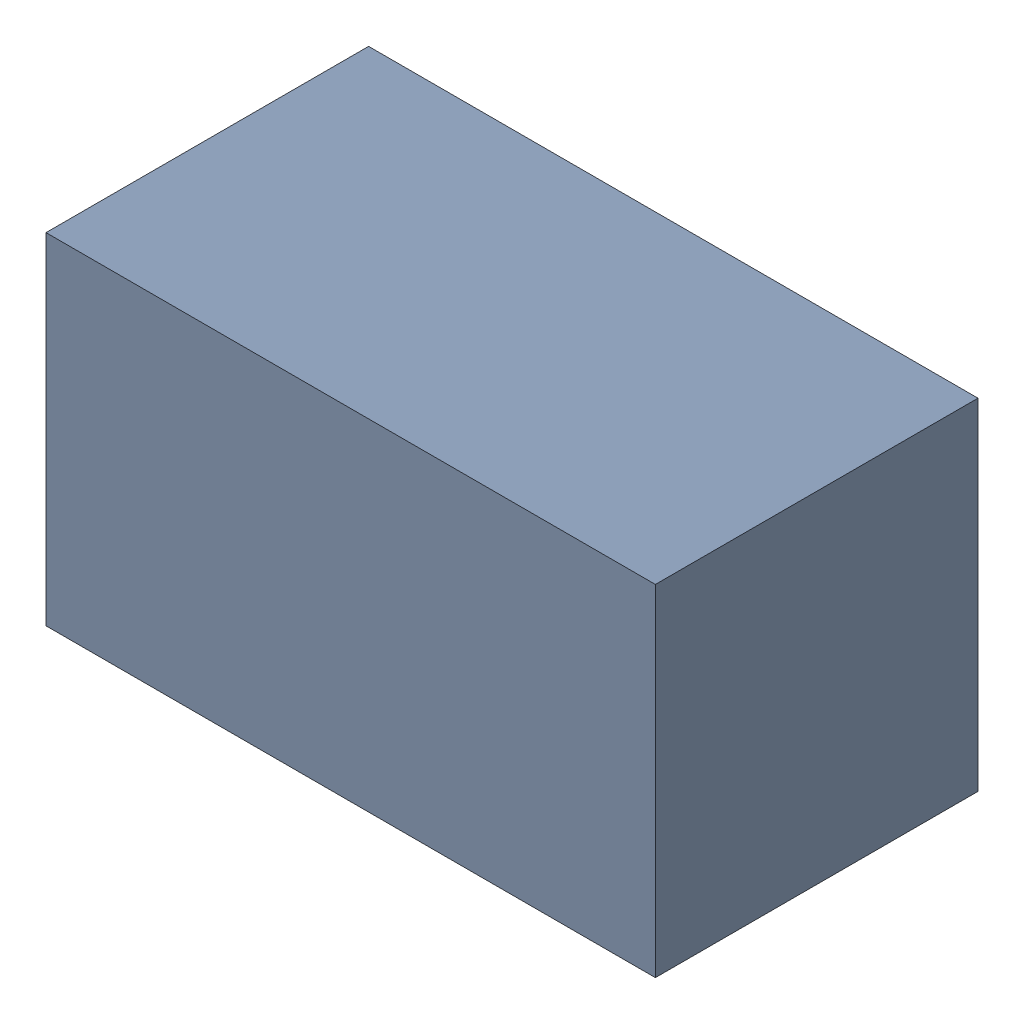
SolidWorks assembly R5, configuration Default. Lengths in mm.
Overall size (1.7 0.95 0.9).
2 component instances, 1 part files, 0 mates.
Components (placement in the parent):
- 580483600-1: 580483600 [Default] at (226.568 108.839 0) size (1.7 0.95 0.9)
  - Extruded_3-1: Extruded_3 [Default] at origin size (1.7 0.95 0.9)
